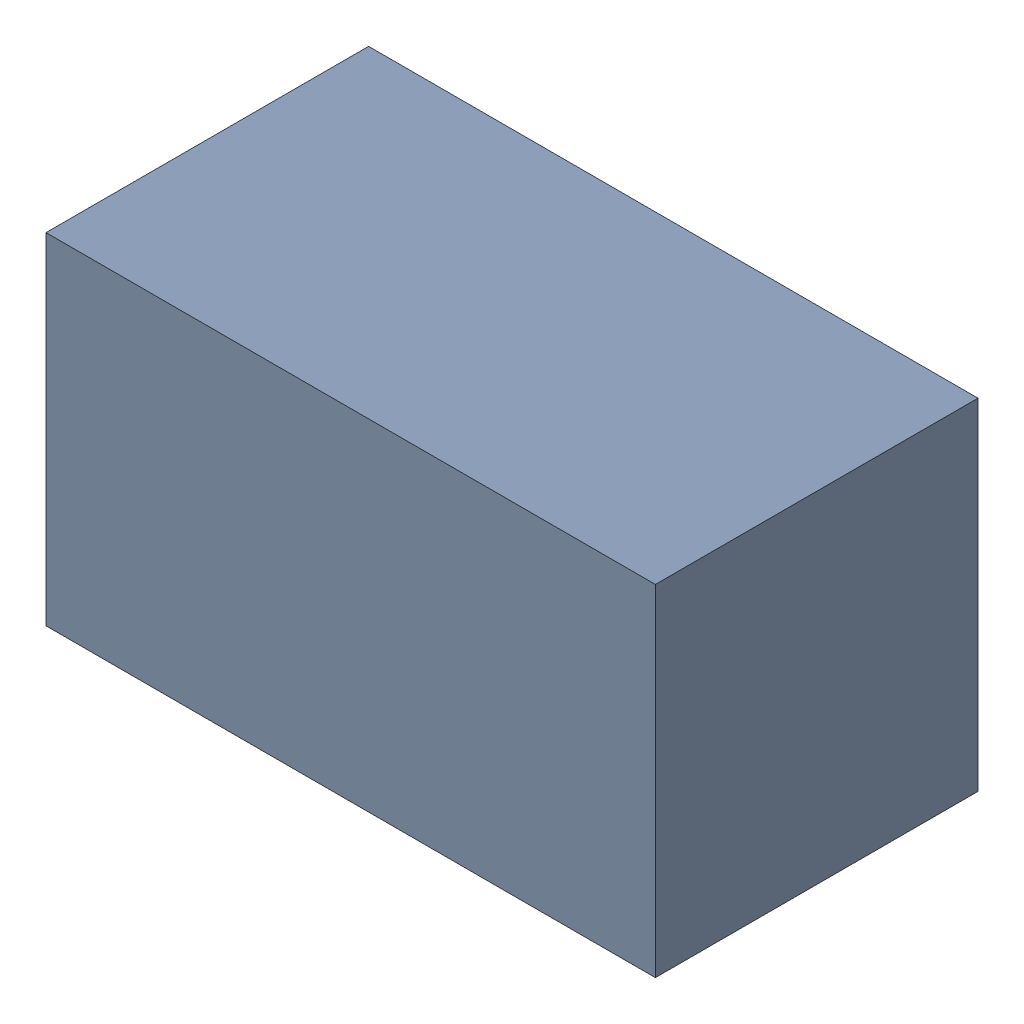
SolidWorks assembly R201, configuration Standard. Lengths in mm.
Overall size (1.7 0.95 0.9).
2 component instances, 1 part files, 0 mates.
Components (placement in the parent):
- 885541288-1: 885541288 [Standard] at (20.01 9.99 0) size (1.7 0.95 0.9)
  - Extruded_10-1: Extruded_10 [Standard] at origin size (1.7 0.95 0.9)
